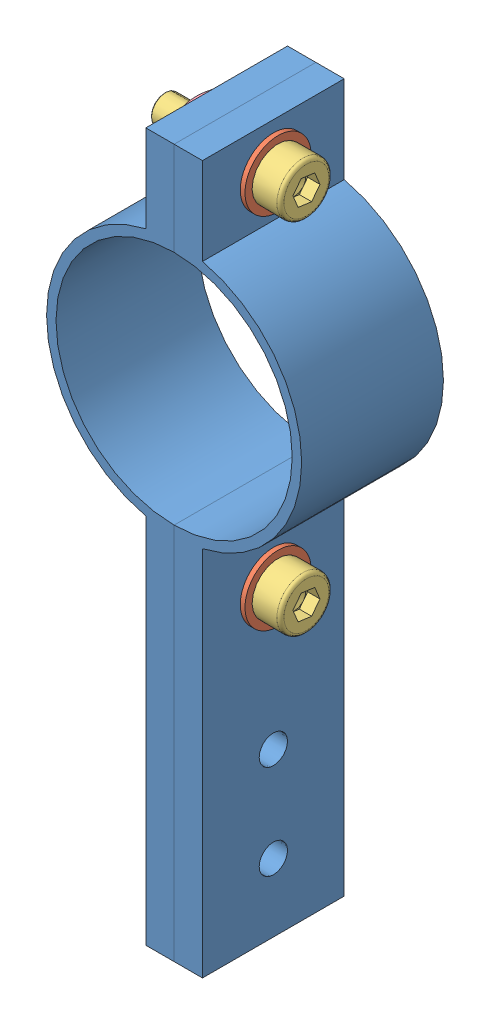
SolidWorks assembly 大管夹具, configuration 默认. Lengths in mm.
Overall size (27 74.91 15).
8 component instances, 4 part files, 15 mates.
Components (placement in the parent):
- 窄夹具-1: 窄夹具 [默认] at (29.1251 11.2528 -7.5) size (13.5 74.91 15)
- 窄夹具-2: 窄夹具 [默认] at (29.1251 11.2528 7.5) x (-1 0 0) z (0 0 -1) size (13.5 74.91 15)
- plain washers-n series-grade a gb-2: plain washers-n series-grade a gb [GB_FASTENER_WASHER_PWNA 3] at (32.6251 28.9495 0) x (0 0 -1) z (1 0 0) size (7 7 0.5)
- plain washers-n series-grade a gb-3: plain washers-n series-grade a gb [GB_FASTENER_WASHER_PWNA 3] at (32.6251 -9.0387 0) x (0 0 -1) z (1 0 0) size (7 7 0.5)
- hexagon socket head cap screws gb-2: hexagon socket head cap screws gb [GB_FASTENER_SCREWS_HSHCS M3X12-N] at (35.6251 -9.0387 0) x (-1 0 0) z (0 0.924225 0.381849) size (15 5.5 5.5)
- hexagon socket head cap screws gb-3: hexagon socket head cap screws gb [GB_FASTENER_SCREWS_HSHCS M3X12-N] at (35.6251 28.9495 0) x (-1 0 0) z (0 0.924225 0.381849) size (15 5.5 5.5)
- hex nuts, style 1-grades ab gb-2: hex nuts, style 1-grades ab gb [GB_FASTENER_NUT_SNAB1 M3-N] at (23.7251 28.9495 0) x (0 0 1) z (-1 0 0) size (6.35 5.5 2.4)
- hex nuts, style 1-grades ab gb-3: hex nuts, style 1-grades ab gb [GB_FASTENER_NUT_SNAB1 M3-N] at (23.7251 -9.0387 0) x (0 0 1) z (-1 0 0) size (6.35 5.5 2.4)
Mates (geometry in assembly coordinates):
- 同心11: concentric anti-aligned: cylinder of 窄夹具-1 through (46.1251 28.9495 0) axis (-1 0 0) radius 1.5; cylinder of 窄夹具-2 through (12.1251 28.9495 0) axis (1 0 0) radius 1.5
- 同心21: concentric anti-aligned: cylinder of 窄夹具-1 through (46.1251 -9.0387 0) axis (-1 0 0) radius 1.5; cylinder of 窄夹具-2 through (12.1251 -9.0387 0) axis (1 0 0) radius 1.5
- 重合11: coincident anti-aligned: plane of 窄夹具-1 through (29.1251 11.2528 7.5) normal (1 0 0); plane of 窄夹具-2 through (29.1251 11.2528 -7.5) normal (-1 0 0)
- 同心3: concentric aligned: cylinder of 窄夹具-2 through (12.1251 28.9495 0) axis (1 0 0) radius 1.5; cylinder of plain washers-n series-grade a gb-2 through (32.1251 28.9495 0) axis (1 0 0) radius 1.6
- 重合2: coincident anti-aligned: plane of 窄夹具-2 through (32.1251 11.2528 -7.5) normal (1 0 0); plane of plain washers-n series-grade a gb-2 through (32.1251 28.9495 0) normal (-1 0 0)
- 同心4: concentric aligned: cylinder of 窄夹具-2 through (12.1251 -9.0387 0) axis (1 0 0) radius 1.5; cylinder of plain washers-n series-grade a gb-3 through (32.1251 -9.0387 0) axis (1 0 0) radius 1.6
- 重合3: coincident anti-aligned: plane of 窄夹具-2 through (32.1251 11.2528 -7.5) normal (1 0 0); plane of plain washers-n series-grade a gb-3 through (32.1251 -9.0387 0) normal (-1 0 0)
- 同心5: concentric aligned: cylinder of plain washers-n series-grade a gb-3 through (32.1251 -9.0387 0) axis (1 0 0) radius 3.5; cylinder of hexagon socket head cap screws gb-2 through (20.6251 -9.0387 0) axis (1 0 0) radius 1.5
- 重合4: coincident anti-aligned: plane of plain washers-n series-grade a gb-3 through (32.6251 -9.0387 0) normal (1 0 0); plane of hexagon socket head cap screws gb-2 through (32.6251 -9.0387 0) normal (-1 0 0)
- 同心6: concentric aligned: cylinder of 窄夹具-2 through (12.1251 28.9495 0) axis (1 0 0) radius 1.5; cylinder of hexagon socket head cap screws gb-3 through (20.6251 28.9495 0) axis (1 0 0) radius 1.5
- 重合5: coincident anti-aligned: plane of plain washers-n series-grade a gb-2 through (32.6251 28.9495 0) normal (1 0 0); plane of hexagon socket head cap screws gb-3 through (32.6251 28.9495 0) normal (-1 0 0)
- 同心7: concentric anti-aligned: cylinder of hexagon socket head cap screws gb-3 through (20.6251 28.9495 0) axis (1 0 0) radius 1.5; cone of hex nuts, style 1-grades ab gb-2 through (26.1251 28.9495 0) axis (-1 0 0)
- 重合6: coincident anti-aligned: plane of 窄夹具-1 through (26.1251 11.2528 7.5) normal (-1 0 0); plane of hex nuts, style 1-grades ab gb-2 through (26.1251 23.4495 0) normal (1 0 0)
- 同心8: concentric aligned: cylinder of 窄夹具-1 through (46.1251 -9.0387 0) axis (-1 0 0) radius 1.5; cone of hex nuts, style 1-grades ab gb-3 through (26.1251 -9.0387 0) axis (-1 0 0)
- 重合7: coincident anti-aligned: plane of 窄夹具-1 through (26.1251 11.2528 7.5) normal (-1 0 0); plane of hex nuts, style 1-grades ab gb-3 through (26.1251 -14.5387 0) normal (1 0 0)
